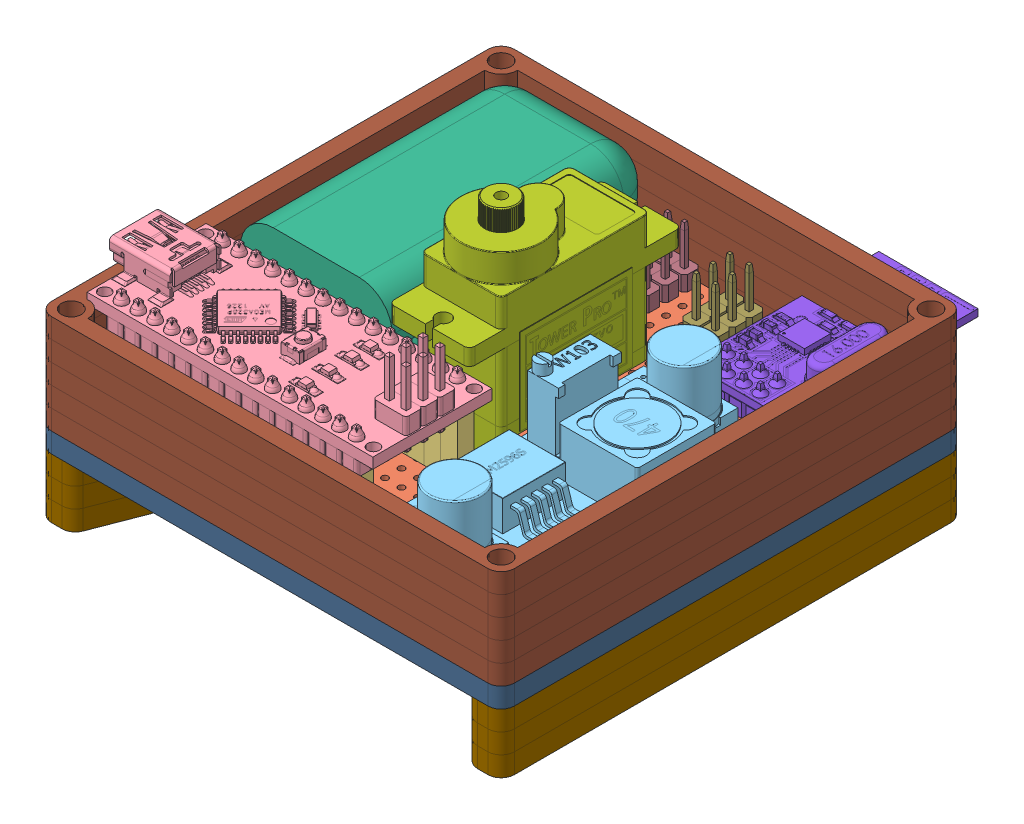
SolidWorks assembly base assembly, configuration Default. Lengths in mm.
Overall size (70 41.85 79.11).
27 component instances, 14 part files, 68 mates.
Components (placement in the parent):
- hex nut style 1_am-1: hex nut style 1_am [B18.2.4.1M - Hex nut, Style 1,  M3 x 0.5 --D-N] at (-15.0478 14.4 2.5048) x (1 0 0) z (0 1 0) size (5.5 6.35 2.4)
- hex nut style 1_am-2: hex nut style 1_am [B18.2.4.1M - Hex nut, Style 1,  M3 x 0.5 --D-N] at (-65.0478 12 2.5048) x (1 0 0) z (0 -1 0) size (5.5 6.35 2.4)
- hex nut style 1_am-3: hex nut style 1_am [B18.2.4.1M - Hex nut, Style 1,  M3 x 0.5 --D-N] at (-15.0478 14.4 52.5048) x (1 0 0) z (0 1 0) size (5.5 6.35 2.4)
- hex nut style 1_am-4: hex nut style 1_am [B18.2.4.1M - Hex nut, Style 1,  M3 x 0.5 --D-N] at (-65.0478 14.4 52.5048) x (1 0 0) z (0 1 0) size (5.5 6.35 2.4)
- pcb-2: pcb [Default] at (-72.9594 14.4 41.2771) x (0 0 1) z (-1 0 0) size (60 1 60)
- Arduino NanoV3 + Female Headers-1: Arduino NanoV3 + Female Headers [Default] at (-32.0594 27.95 40.8489) x (-1 0 0) z (0 0 1) size (38.1 11.45 17.78)
- arduino nano-1: arduino nano [Default] at (-36.1294 26.35 42.1189) x (-1 0 0) z (0 0 -1) size (45 18.6 18)
- LM2596 - small buck-1: LM2596 - small buck [Default] at (-14.6157 36.0469 15.8857) x (0 0 1) z (0 1 0) size (43.33 21.52 14.13)
- battery-1: battery [Default] at (-61.9173 22.4 17.6773) size (23 7 40)
- battery-2: battery [Default] at (-61.709 15.4 17.6773) size (23 7 40)
- SG90 - Micro Servo 9g - Tower Pro.1-1: SG90 - Micro Servo 9g - Tower Pro.1 [Peça] at (-42.9594 22.55 23.5273) x (0 0 -1) z (1 0 0) size (32.1 29.95 12.4)
- nRF24L01+_enhanced-1: nRF24L01+_enhanced [Default<As Machined>] at (-22.4594 18.449 -0.9285) x (0 0 -1) z (1 0 0) size (29 12.85 15)
- stage-1: stage [Default] at (-42.9594 0 28.6773) size (70 3 70)
- base1-1: base1 [Default] at (-42.9594 12 28.6773) x (-1 0 0) z (0 0 1) size (70 3 70)
- stage-2: stage [Default] at (-42.9594 3 28.6773) size (70 3 70)
- stage-3: stage [Default] at (-42.9594 6 28.6773) size (70 3 70)
- walls-1: walls [Default] at (-42.9594 12 28.6773) size (70 3 70)
- walls-2: walls [Default] at (-42.9594 15 28.6773) size (70 3 70)
- walls-3: walls [Default] at (-42.9594 18 28.6773) size (70 3 70)
- walls-4: walls [Default] at (-42.9594 21 28.6773) size (70 3 70)
- walls-5: walls [Default] at (-42.9594 24 28.6773) size (70 3 70)
- Header, Male, 2.54mm, 1x3-1: Header, Male, 2.54mm, 1x3 [Default] at (-33.4499 15.146 0.698) x (0 0 -1) z (1 0 0) size (7.62 11.54 2.54)
- Header, Male, 2.54mm, 1x3-2: Header, Male, 2.54mm, 1x3 [Default] at (-36.3022 15.146 0.7513) x (0 0 -1) z (1 0 0) size (7.62 11.54 2.54)
- Header, Male, 2.54mm, 1x2-1: Header, Male, 2.54mm, 1x2 [Default] at (-44.122 15.146 5.6481) size (5.08 11.54 2.54)
- Header, Male, 2.54mm, 1x2-2: Header, Male, 2.54mm, 1x2 [Default] at (-44.0543 15.146 2.787) size (5.08 11.54 2.54)
- Header, Male, 2.54mm, 1x2-3: Header, Male, 2.54mm, 1x2 [Default] at (-43.947 15.146 -0.0213) size (5.08 11.54 2.54)
- base1nano-1: base1nano [Default] at (-42.9594 27 28.6773) x (0 0 1) z (-1 0 0) size (70 3 70) (hidden)
Mates (geometry in assembly coordinates):
- Coincident28: coincident anti-aligned: plane of stage-1 through (-41.814 0 3.6773) normal (0 -1 0); plane of assembly through (0 0 0) normal (0 1 0)
- Coincident29: coincident anti-aligned: plane of stage-1 through (-41.814 3 3.6773) normal (0 1 0); plane of stage-2 through (-41.814 3 3.6773) normal (0 -1 0)
- Coincident30: coincident aligned: plane of stage-1 through (-77.9594 3 -6.3227) normal (-1 0 0); plane of stage-2 through (-77.9594 6 -6.3227) normal (-1 0 0)
- Concentric11: concentric aligned: cylinder of stage-1 through (-75.4594 0 61.1773) axis (0 1 0) radius 1.4881; cylinder of stage-2 through (-75.4594 3 61.1773) axis (0 1 0) radius 1.4881
- Coincident31: coincident anti-aligned: plane of stage-2 through (-41.814 6 3.6773) normal (0 1 0); plane of stage-3 through (-41.814 6 3.6773) normal (0 -1 0)
- Coincident32: coincident aligned: plane of stage-1 through (-77.9594 3 -6.3227) normal (-1 0 0); plane of stage-3 through (-77.9594 9 -6.3227) normal (-1 0 0)
- Concentric12: concentric aligned: cylinder of stage-1 through (-75.4594 0 61.1773) axis (0 1 0) radius 1.4881; cylinder of stage-3 through (-75.4594 6 61.1773) axis (0 1 0) radius 1.4881
- Coincident35: coincident anti-aligned: plane of base1-1 through (-42.9594 9 28.6773) normal (0 -1 0); plane of stage-3 through (-41.814 9 3.6773) normal (0 1 0)
- Coincident36: coincident aligned: plane of base1-1 through (-77.9594 9 -6.3227) normal (-1 0 0); plane of stage-2 through (-77.9594 6 -6.3227) normal (-1 0 0)
- Concentric14: concentric aligned: cylinder of base1-1 through (-75.4594 9 61.1773) axis (0 1 0) radius 1.5; cylinder of stage-3 through (-75.4594 6 61.1773) axis (0 1 0) radius 1.4881
- Coincident37: coincident anti-aligned: plane of base1-1 through (-42.9594 12 28.6773) normal (0 1 0); plane of walls-1 through (-42.9594 12 28.6773) normal (0 -1 0)
- Coincident38: coincident aligned: plane of base1-1 through (-77.9594 9 -6.3227) normal (-1 0 0); plane of walls-1 through (-77.9594 15 -6.3227) normal (-1 0 0)
- Concentric15: concentric anti-aligned: cylinder of base1-1 through (-75.4594 9 61.1773) axis (0 1 0) radius 1.5; cylinder of walls-1 through (-75.4594 15 61.1773) axis (0 -1 0) radius 1.5
- Coincident39: coincident anti-aligned: plane of walls-1 through (-42.9594 15 28.6773) normal (0 1 0); plane of walls-2 through (-42.9594 15 28.6773) normal (0 -1 0)
- Coincident40: coincident aligned: plane of base1-1 through (-77.9594 9 -6.3227) normal (-1 0 0); plane of walls-2 through (-77.9594 18 -6.3227) normal (-1 0 0)
- Concentric16: concentric anti-aligned: cylinder of base1-1 through (-75.4594 9 61.1773) axis (0 1 0) radius 1.5; cylinder of walls-2 through (-75.4594 18 61.1773) axis (0 -1 0) radius 1.5
- Coincident41: coincident aligned: plane of base1-1 through (-77.9594 9 -6.3227) normal (-1 0 0); plane of walls-3 through (-77.9594 21 -6.3227) normal (-1 0 0)
- Concentric17: concentric anti-aligned: cylinder of base1-1 through (-75.4594 9 61.1773) axis (0 1 0) radius 1.5; cylinder of walls-3 through (-75.4594 21 61.1773) axis (0 -1 0) radius 1.5
- Coincident42: coincident anti-aligned: plane of walls-2 through (-42.9594 18 28.6773) normal (0 1 0); plane of walls-3 through (-42.9594 18 28.6773) normal (0 -1 0)
- Coincident43: coincident aligned: plane of base1-1 through (-77.9594 9 -6.3227) normal (-1 0 0); plane of walls-4 through (-77.9594 24 -6.3227) normal (-1 0 0)
- Concentric18: concentric anti-aligned: cylinder of base1-1 through (-75.4594 9 61.1773) axis (0 1 0) radius 1.5; cylinder of walls-4 through (-75.4594 24 61.1773) axis (0 -1 0) radius 1.5
- Coincident44: coincident anti-aligned: plane of walls-3 through (-42.9594 21 28.6773) normal (0 1 0); plane of walls-4 through (-42.9594 21 28.6773) normal (0 -1 0)
- Coincident45: coincident aligned: plane of base1-1 through (-77.9594 9 -6.3227) normal (-1 0 0); plane of walls-5 through (-77.9594 27 -6.3227) normal (-1 0 0)
- Concentric19: concentric anti-aligned: cylinder of base1-1 through (-75.4594 9 61.1773) axis (0 1 0) radius 1.5; cylinder of walls-5 through (-75.4594 27 61.1773) axis (0 -1 0) radius 1.5
- Coincident46: coincident anti-aligned: plane of walls-4 through (-42.9594 24 28.6773) normal (0 1 0); plane of walls-5 through (-42.9594 24 28.6773) normal (0 -1 0)
- Coincident49: coincident anti-aligned: plane of hex nut style 1_am-3 through (-20.5478 12 52.5048) normal (0 -1 0); plane of base1-1 through (-42.9594 12 28.6773) normal (0 1 0)
- Concentric21: concentric aligned: cylinder of hex nut style 1_am-3 through (-15.0478 12 52.5048) axis (0 1 0) radius 1.25; circle of assembly
- Coincident50: coincident anti-aligned: plane of hex nut style 1_am-1 through (-20.5478 12 2.5048) normal (0 -1 0); plane of base1-1 through (-42.9594 12 28.6773) normal (0 1 0)
- Concentric22: concentric aligned: cylinder of hex nut style 1_am-1 through (-15.0478 12 2.5048) axis (0 1 0) radius 1.25; circle of assembly
- Coincident51: coincident anti-aligned: plane of hex nut style 1_am-4 through (-70.5478 12 52.5048) normal (0 -1 0); plane of base1-1 through (-42.9594 12 28.6773) normal (0 1 0)
- Concentric23: concentric aligned: cylinder of hex nut style 1_am-4 through (-65.0478 12 52.5048) axis (0 1 0) radius 1.25; circle of assembly
- Coincident52: coincident anti-aligned: plane of hex nut style 1_am-2 through (-70.5478 12 2.5048) normal (0 -1 0); plane of base1-1 through (-42.9594 12 28.6773) normal (0 1 0)
- Concentric24: concentric anti-aligned: cylinder of hex nut style 1_am-2 through (-65.0478 14.4 2.5048) axis (0 -1 0) radius 1.25; circle of assembly
- Coincident53: coincident anti-aligned: plane of hex nut style 1_am-4 through (-70.5478 14.4 52.5048) normal (0 1 0); plane of pcb-2 through (-72.9594 14.4 41.2771) normal (0 -1 0)
- Concentric25: concentric anti-aligned: cylinder of SG90 - Micro Servo 9g - Tower Pro.1-1 through (-42.9594 38.75 28.6773) axis (0 -1 0) radius 6.1; circle of assembly
- Parallel8: parallel aligned: plane of SG90 - Micro Servo 9g - Tower Pro.1-1 through (-48.2094 12 12.2773) normal (0 0 -1); plane of walls-5 through (-77.9594 27 -6.3227) normal (0 0 -1)
- Coincident55: coincident anti-aligned: plane of SG90 - Micro Servo 9g - Tower Pro.1-1 through (-37.7094 12 33.9273) normal (0 -1 0); circle of assembly
- Parallel10: parallel: plane of SG90 - Micro Servo 9g - Tower Pro.1-1 through (-49.0594 30.2 38.7273) normal (-1 0 0); line of assembly
- Coincident58: coincident anti-aligned: plane of pcb-2 through (-49.0594 15.4 39.8789) normal (1 0 0); plane of SG90 - Micro Servo 9g - Tower Pro.1-1 through (-49.0594 30.2 38.7273) normal (-1 0 0)
- Lock2: lock: unknown of pcb-2; unknown of walls-5
- Coincident60: coincident anti-aligned: plane of pcb-2 through (-72.9594 15.4 41.2771) normal (0 1 0); plane of battery-2 through (-61.709 15.4 17.6773) normal (0 -1 0)
- Coincident64: coincident aligned: plane of battery-1 through (-73.4173 29.4 37.6773) normal (0 0 1); plane of battery-2 through (-73.209 22.4 37.6773) normal (0 0 1)
- Coincident65: coincident anti-aligned: plane of battery-1 through (-61.9173 22.4 17.6773) normal (0 -1 0); plane of battery-2 through (-61.709 22.4 17.6773) normal (0 1 0)
- Distance2: distance = 26 mm aligned: plane of battery-2 through (-73.209 22.4 37.6773) normal (0 0 1); plane of walls-4 through (-77.9594 24 63.6773) normal (0 0 1)
- Coincident67: coincident anti-aligned: plane of pcb-2 through (-72.9594 15.4 41.2771) normal (0 1 0); plane of LM2596 - small buck-1 through (-23.7804 15.4 36.9128) normal (0 -1 0)
- Coincident68: coincident: line of pcb-2 through (-72.9594 15.4 58.6289) axis (1 0 0); plane of LM2596 - small buck-1 through (-16.909 16.9539 58.6289) normal (0 0 1)
- Coincident69: coincident anti-aligned: plane of pcb-2 through (-72.9594 15.4 41.2771) normal (0 1 0); plane of nRF24L01+_enhanced-1 through (-19.0894 15.4 10.8015) normal (0 -1 0)
- Distance3: distance = 2 mm: plane of nRF24L01+_enhanced-1 through (-14.9594 18.949 13.5715) normal (1 0 0); line of pcb-2 through (-12.9594 15.4 58.6289) axis (0 0 -1)
- Coincident72: coincident anti-aligned: plane of pcb-2 through (-72.9594 15.4 41.2771) normal (0 1 0); plane of Arduino NanoV3 + Female Headers-1 through (-58.9894 15.4 42.1189) normal (0 -1 0)
- Coincident73: coincident: line of pcb-2 through (-72.9594 15.4 58.6289) axis (1 0 0); plane of Arduino NanoV3 + Female Headers-1 through (-39.9394 15.4 58.6289) normal (0 0 1)
- Coincident74: coincident: line of pcb-2 through (-72.9594 15.4 -1.3711) axis (0 0 1); plane of Arduino NanoV3 + Female Headers-1 through (-72.9594 15.4 56.0889) normal (-1 0 0)
- Coincident75: coincident anti-aligned: plane of Arduino NanoV3 + Female Headers-1 through (-53.9094 23.85 57.3589) normal (0 1 0); plane of arduino nano-1 through (-36.8994 23.85 56.5889) normal (0 -1 0)
- Coincident76: coincident aligned: plane of Arduino NanoV3 + Female Headers-1 through (-50.0994 15.4 58.6289) normal (0 0 1); plane of arduino nano-1 through (-47.0594 23.85 58.6289) normal (0 0 1)
- Coincident77: coincident aligned: plane of Arduino NanoV3 + Female Headers-1 through (-34.8594 15.4 58.6289) normal (1 0 0); plane of arduino nano-1 through (-34.8594 23.85 58.1289) normal (1 0 0)
- Lock3: lock: unknown of base1-1
- Coincident79: coincident anti-aligned: plane of pcb-2 through (-72.9594 15.4 41.2771) normal (0 1 0); plane of Header, Male, 2.54mm, 1x3-1 through (-33.4499 15.4 5.778) normal (0 -1 0)
- Parallel13: parallel: line of pcb-2 through (-12.9594 15.4 58.6289) axis (0 0 -1); plane of Header, Male, 2.54mm, 1x3-1 through (-34.7199 17.686 4.508) normal (-1 0 0)
- Coincident81: coincident anti-aligned: plane of pcb-2 through (-72.9594 15.4 41.2771) normal (0 1 0); plane of Header, Male, 2.54mm, 1x3-2 through (-36.3022 15.4 5.8313) normal (0 -1 0)
- Parallel14: parallel: line of pcb-2 through (-12.9594 15.4 58.6289) axis (0 0 -1); plane of Header, Male, 2.54mm, 1x3-2 through (-37.5722 17.686 4.5613) normal (-1 0 0)
- Parallel16: parallel aligned: plane of walls-2 through (-77.9594 18 -6.3227) normal (0 0 -1); plane of Header, Male, 2.54mm, 1x2-1 through (-45.392 17.686 4.3781) normal (0 0 -1)
- Coincident86: coincident anti-aligned: plane of pcb-2 through (-72.9594 15.4 41.2771) normal (0 1 0); plane of Header, Male, 2.54mm, 1x2-1 through (-46.662 15.4 5.6481) normal (0 -1 0)
- Parallel18: parallel aligned: plane of walls-2 through (-77.9594 18 -6.3227) normal (0 0 -1); plane of Header, Male, 2.54mm, 1x2-2 through (-45.3243 17.686 1.517) normal (0 0 -1)
- Coincident87: coincident anti-aligned: plane of pcb-2 through (-72.9594 15.4 41.2771) normal (0 1 0); plane of Header, Male, 2.54mm, 1x2-2 through (-46.5943 15.4 2.787) normal (0 -1 0)
- Parallel19: parallel aligned: plane of walls-2 through (-77.9594 18 -6.3227) normal (0 0 -1); plane of Header, Male, 2.54mm, 1x2-3 through (-45.217 17.686 -1.2913) normal (0 0 -1)
- Coincident88: coincident anti-aligned: plane of pcb-2 through (-72.9594 15.4 41.2771) normal (0 1 0); plane of Header, Male, 2.54mm, 1x2-3 through (-46.487 15.4 -0.0213) normal (0 -1 0)
- Concentric26: concentric aligned: cylinder of walls-5 through (-10.4594 27 -3.8227) axis (0 -1 0) radius 1.5; cylinder of base1nano-1 through (-10.4594 30 -3.8227) axis (0 -1 0) radius 1.5
- Coincident90: coincident anti-aligned: plane of walls-5 through (-42.9594 27 28.6773) normal (0 1 0); plane of base1nano-1 through (-42.9594 27 28.6773) normal (0 -1 0)
- Coincident91: coincident aligned: plane of walls-4 through (-77.9594 24 -6.3227) normal (0 0 -1); plane of base1nano-1 through (-7.9594 30 -6.3227) normal (0 0 -1)
